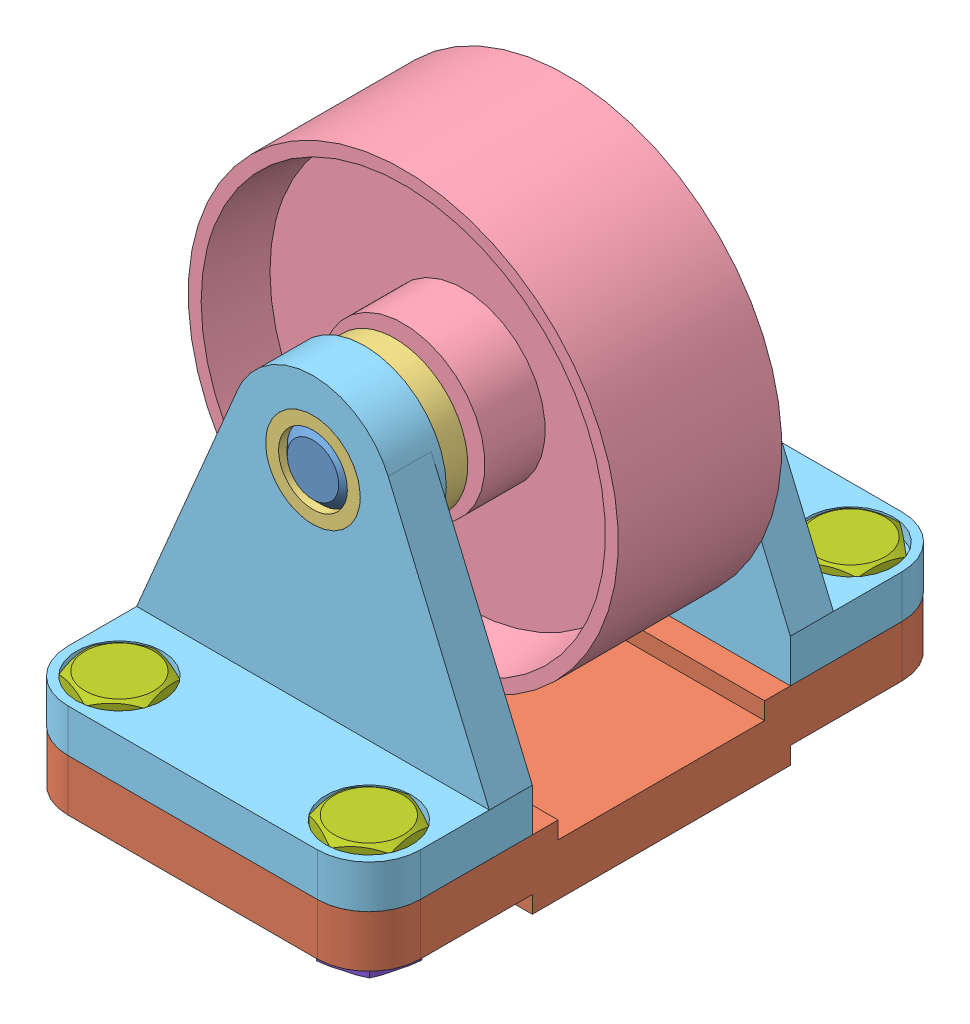
SolidWorks assembly Ensamblaje1, configuration Predeterminado. Lengths in mm.
Overall size (125.45 136.73 139.17).
19 component instances, 8 part files, 39 mates.
Components (placement in the parent):
- Axial-1: Axial [Predeterminado] at (-116.9137 71.5164 119.2825) x (-0.749243 -0.662295 0) z (0.662295 -0.749243 0) size (22 80 22)
- Base-1: Base [Predeterminado] at (-116.9137 -2.4836 79.2825) size (82 16 136)
- Rosca-1: Rosca [Predeterminado] at (-116.9137 71.5164 39.2825) x (1 0 0) z (0 -1 0) size (34 19 34)
- Rueda-1: Rueda [Predeterminado] at (-116.9137 71.5164 79.2825) x (0 0 1) z (-0.95367 0.300855 0) size (38 100 100)
- Soporte Axial-1: Soporte Axial [Predeterminado] at (-157.9137 90.5164 107.2825) x (1 0 0) z (0 0 -1) size (82 77 40)
- Soporte Axial-2: Soporte Axial [Predeterminado] at (-75.9137 90.5164 51.2825) x (-1 0 0) z (0 0 1) size (82 77 40)
- Rosca-2: Rosca [Predeterminado] at (-116.9137 71.5164 119.2825) x (0.98932 0.145763 0) z (-0.145763 0.98932 0) size (34 19 34)
- arandela-1: arandela [Predeterminado] at (-145.9137 0.5164 23.2825) x (-0.036133 0 0.999347) z (-0.999347 0 -0.036133) size (20 1 20)
- arandela-4: arandela [Predeterminado] at (-87.9137 0.5164 23.2825) size (20 1 20)
- tornillo-1: tornillo [Predeterminado] at (-145.9137 20.5164 135.2825) x (0.944045 0 0.329818) z (-0.329818 0 0.944045) size (20 27 17.32)
- tornillo-2: tornillo [Predeterminado] at (-87.9137 20.5164 23.2825) x (0.930789 0 -0.365556) z (0.365556 0 0.930789) size (20 27 17.32)
- tornillo-3: tornillo [Predeterminado] at (-87.9137 20.5164 135.2825) x (-0.814471 0 0.580205) z (-0.580205 0 -0.814471) size (20 27 17.32)
- tornillo-4: tornillo [Predeterminado] at (-145.9137 20.5164 23.2825) x (0.984146 0 0.177358) z (-0.177358 0 0.984146) size (20 27 17.32)
- tuerca-1: tuerca [Predeterminado] at (-145.9137 -1.4836 23.2825) x (0.76657 0 0.642161) z (-0.642161 0 0.76657) size (20 2 17.32)
- tuerca-3: tuerca [Predeterminado] at (-87.9137 -1.4836 23.2825) x (0.036857 0 0.999321) z (-0.999321 0 0.036857) size (20 2 17.32)
- arandela-5: arandela [Predeterminado] at (-145.9137 0.5164 135.2825) x (0.278303 0 0.960493) z (-0.960493 0 0.278303) size (20 1 20)
- arandela-6: arandela [Predeterminado] at (-87.9137 0.5164 135.2825) x (-0.653945 0 -0.756542) z (0.756542 0 -0.653945) size (20 1 20)
- tuerca-5: tuerca [Predeterminado] at (-145.9137 -1.4836 135.2825) x (-0.402195 0 0.915554) z (-0.915554 0 -0.402195) size (20 2 17.32)
- tuerca-6: tuerca [Predeterminado] at (-87.9137 -1.4836 135.2825) x (0.715472 0 0.698641) z (-0.698641 0 0.715472) size (20 2 17.32)
Mates (geometry in assembly coordinates):
- Coincidente6: coincident anti-aligned: plane of Base-1 through (-145.9137 13.5164 23.2825) normal (0 1 0); plane of Soporte Axial-1 through (-75.9137 13.5164 109.2825) normal (0 -1 0)
- Coincidente10: coincident anti-aligned: circle of Base-1; circle of Soporte Axial-1
- Coincidente11: coincident aligned: cylinder of Base-1 through (-145.9137 -2.4836 135.2825) axis (0 1 0) radius 5.5; circle of Soporte Axial-1
- Coincidente12: coincident anti-aligned: plane of Base-1 through (-145.9137 13.5164 23.2825) normal (0 1 0); plane of Soporte Axial-2 through (-157.9137 13.5164 49.2825) normal (0 -1 0)
- Concéntrica1: concentric aligned: cylinder of Base-1 through (-87.9137 -2.4836 23.2825) axis (0 1 0) radius 5.5; cylinder of Soporte Axial-2 through (-87.9137 13.5164 23.2825) axis (0 1 0) radius 5.5
- Coincidente17: coincident aligned: cylinder of Base-1 through (-145.9137 -2.4836 23.2825) axis (0 1 0) radius 5.5; circle of Soporte Axial-2
- Coincidente23: coincident anti-aligned: plane of Rosca-2 through (-133.7322 69.0385 107.2825) normal (0 0 1); circle of Soporte Axial-1
- Coincidente24: coincident aligned: circle of Soporte Axial-1; circle of Rosca-2
- Coincidente25: coincident anti-aligned: plane of Rosca-1 through (-133.9137 71.5164 51.2825) normal (0 0 -1); circle of Soporte Axial-2
- Coincidente26: coincident aligned: circle of Rosca-1; plane of Soporte Axial-2 through (-157.9137 23.5164 39.2825) normal (0 0 -1)
- Coincidente27: coincident aligned: circle of Rosca-1; circle of Soporte Axial-2
- Coincidente28: coincident anti-aligned: circle of Rosca-1; cylinder of Axial-1 through (-116.9137 71.5164 39.2825) axis (0 0 1) radius 8
- Coincidente29: coincident aligned: circle of Axial-1; plane of Soporte Axial-2 through (-157.9137 23.5164 39.2825) normal (0 0 -1)
- Ancho1: width anti-aligned: plane of Rosca-2 through (-124.8283 70.3503 100.2825) normal (0 0 -1); plane of Rueda-1 through (-124.9137 71.5164 58.2825) normal (0 0 1); plane of Rosca-1 through (-111.1975 89.6362 98.2825) normal (0 0 1); plane of Rueda-1 through (-113.6043 82.0068 60.2825) normal (0 0 -1)
- Concéntrica3: concentric anti-aligned: cylinder of Axial-1 through (-116.9137 71.5164 59.2825) axis (0 0 1) radius 11; cylinder of Rueda-1 through (-116.9137 71.5164 64.5212) axis (0 0 -1) radius 11
- Coincidente32: coincident anti-aligned: plane of Soporte Axial-1 through (-87.9137 20.5164 135.2825) normal (0 1 0); plane of tornillo-3 through (-87.9137 20.5164 135.2825) normal (0 -1 0)
- Tangente3: tangent: curve of Base-1 through (-87.9137 -2.4836 135.2825) axis (0 1 0) radius 5.5; edge_curve of tornillo-3
- Coincidente38: coincident anti-aligned: plane of Soporte Axial-1 through (-145.9137 20.5164 135.2825) normal (0 1 0); plane of tornillo-1 through (-145.9137 20.5164 135.2825) normal (0 -1 0)
- Tangente4: tangent: cylinder of Base-1 through (-145.9137 -2.4836 135.2825) axis (0 1 0) radius 5.5; edge_curve of tornillo-1
- Coincidente42: coincident anti-aligned: plane of Soporte Axial-2 through (-145.9137 20.5164 23.2825) normal (0 1 0); plane of tornillo-4 through (-145.9137 20.5164 23.2825) normal (0 -1 0)
- Tangente9: tangent: cylinder of Soporte Axial-2 through (-145.9137 13.5164 23.2825) axis (0 1 0) radius 5.5; edge_curve of tornillo-4
- Concéntrica11: concentric aligned: circle of Soporte Axial-2; circle of tornillo-4
- Concéntrica12: concentric aligned: cylinder of Soporte Axial-1 through (-87.9137 20.5164 135.2825) axis (0 1 0) radius 10; circle of tornillo-3
- Concéntrica13: concentric aligned: circle of Soporte Axial-1; circle of tornillo-1
- Coincidente44: coincident anti-aligned: plane of Soporte Axial-2 through (-87.9137 20.5164 23.2825) normal (0 1 0); plane of tornillo-2 through (-87.9137 20.5164 23.2825) normal (0 -1 0)
- Tangente10: tangent: cylinder of Base-1 through (-87.9137 -2.4836 23.2825) axis (0 1 0) radius 5.5; edge_curve of tornillo-2
- Paralelo1: parallel aligned: plane of Soporte Axial-2 through (-87.9137 20.5164 23.2825) normal (0 1 0); plane of tornillo-2 through (-87.9137 24.5164 23.2825) normal (0 1 0)
- Paralelo2: parallel aligned: plane of Soporte Axial-2 through (-87.9137 20.5164 23.2825) normal (0 1 0); plane of tornillo-2 through (-87.9137 24.5164 23.2825) normal (0 1 0)
- Concéntrica14: concentric aligned: cylinder of Soporte Axial-2 through (-87.9137 13.5164 23.2825) axis (0 1 0) radius 5.5; circle of tornillo-2
- Concéntrica15: concentric aligned: circle of Base-1; circle of arandela-1
- Coincidente51: coincident anti-aligned: plane of Base-1 through (-75.9137 1.5164 79.2825) normal (0 -1 0); circle of arandela-1
- Concéntrica16: concentric anti-aligned: circle of Base-1; circle of arandela-4
- Coincidente52: coincident anti-aligned: plane of Base-1 through (-75.9137 1.5164 79.2825) normal (0 -1 0); circle of arandela-4
- Coincidente53: coincident aligned: circle of arandela-1; circle of tuerca-1
- Coincidente54: coincident aligned: circle of arandela-4; circle of tuerca-3
- Coincidente57: coincident aligned: circle of Base-1; circle of arandela-5
- Coincidente58: coincident anti-aligned: circle of Base-1; circle of arandela-6
- Coincidente59: coincident aligned: circle of arandela-5; circle of tuerca-5
- Coincidente60: coincident aligned: circle of arandela-6; circle of tuerca-6
